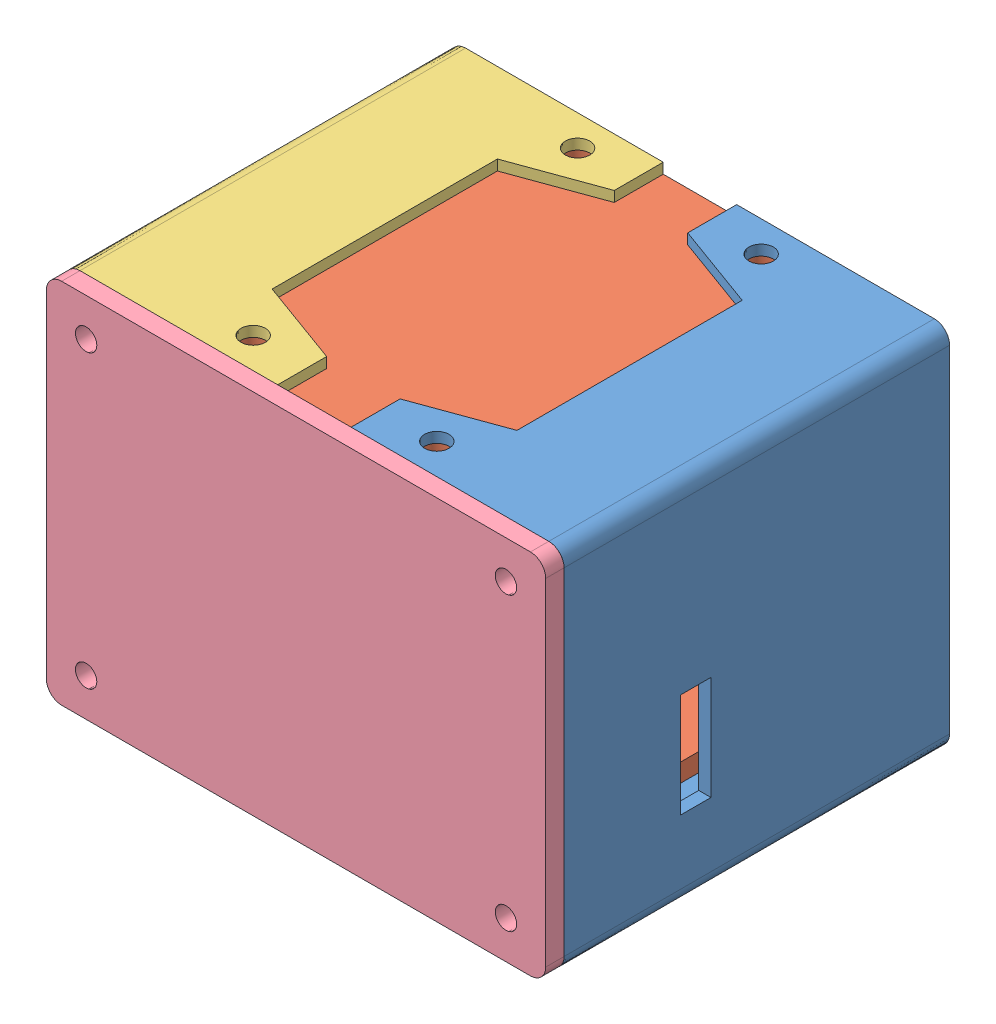
SolidWorks assembly caja V1, configuration Predeterminado. Lengths in mm.
Overall size (81.6 60 66).
6 component instances, 5 part files, 13 mates.
Components (placement in the parent):
- Tapa frontal-1: Tapa frontal [Predeterminado] at origin size (34.8 60 63)
- Tapa lateral-1: Tapa lateral [Predeterminado] at (0 28.3 31.5) x (1 0 0) z (0 -1 0) size (50 63 3)
- Tapa lateral-2: Tapa lateral [Predeterminado] at (0 -25.3 31.5) x (1 0 0) z (0 -1 0) size (50 63 3)
- Tapa trasera-1: Tapa trasera [Predeterminado] x (-1 0 0) z (0 0 1) size (34.8 60 63)
- Tapa inferior-2: Tapa inferior [Predeterminado] at (0 0 -3) x (1 0 0) z (0 -1 0) size (81.6 3 60) (hidden)
- Tapa superior-1: Tapa superior [Predeterminado] at (0 0 63) x (1 0 0) z (0 -1 0) size (81.6 3 60)
Mates (geometry in assembly coordinates):
- Coincidente1: coincident anti-aligned: plane of Tapa frontal-1 through (0 28.3 63) normal (0 -1 0); plane of Tapa lateral-1 through (0 28.3 31.5) normal (0 1 0)
- Coincidente2: coincident aligned: plane of Tapa frontal-1 through (38.3 27.5 0) normal (0 0 -1); plane of Tapa lateral-1 through (-25 25.3 0) normal (0 0 -1)
- Coincidente3: coincident anti-aligned: plane of Tapa frontal-1 through (25 28.3 63) normal (-1 0 0); plane of Tapa lateral-1 through (25 25.3 63) normal (1 0 0)
- Coincidente4: coincident anti-aligned: plane of Tapa frontal-1 through (0 -28.3 63) normal (0 1 0); plane of Tapa lateral-2 through (0 -28.3 31.5) normal (0 -1 0)
- Coincidente6: coincident anti-aligned: line of Tapa frontal-1 through (25 -21.3 0) axis (0 -1 0); line of Tapa lateral-2 through (25 -28.3 0) axis (0 1 0)
- Coincidente9: coincident aligned: plane of Tapa frontal-1 through (38.3 27.5 0) normal (0 0 -1); plane of Tapa trasera-1 through (-38.3 -27.5 0) normal (0 0 -1)
- Coincidente10: coincident anti-aligned: plane of Tapa lateral-2 through (-25 -28.3 63) normal (-1 0 0); plane of Tapa trasera-1 through (-25 -28.3 63) normal (1 0 0)
- Coincidente11: coincident anti-aligned: plane of Tapa lateral-2 through (0 -28.3 31.5) normal (0 -1 0); plane of Tapa trasera-1 through (0 -28.3 63) normal (0 1 0)
- Coincidente16: coincident anti-aligned: plane of Tapa frontal-1 through (38.3 27.5 0) normal (0 0 -1); plane of Tapa inferior-2 through (38.3 27.5 0) normal (0 0 1)
- Concéntrica1: concentric aligned: circle of Tapa trasera-1; circle of Tapa inferior-2
- Coincidente17: coincident aligned: plane of Tapa frontal-1 through (0 -30 63) normal (0 -1 0); plane of Tapa inferior-2 through (38.3 -30 0) normal (0 -1 0)
- Coincidente18: coincident aligned: circle of Tapa trasera-1; circle of Tapa superior-1
- Coincidente19: coincident aligned: plane of Tapa trasera-1 through (0 -30 63) normal (0 -1 0); plane of Tapa superior-1 through (-38.3 -30 66) normal (0 -1 0)
